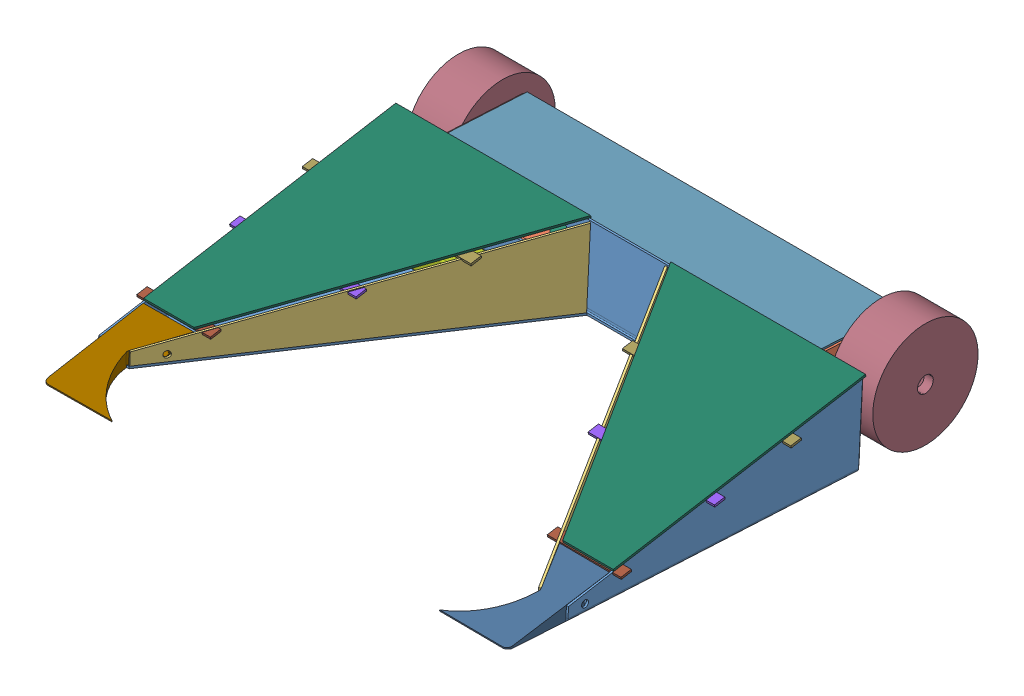
SolidWorks assembly Montagem, configuration Valor predeterminado. Lengths in mm.
Overall size (462 104.5 447.91).
26 component instances, 16 part files, 76 mates.
Components (placement in the parent):
- Base_triangulo-1: Base_triangulo [Valor predeterminado] at (18.3042 -43.9927 399.2511) size (446.01 74.77 283.15)
- Base_retangulo-1: Base_retangulo [Valor predeterminado] at (18.3042 -27.2137 284.6524) x (1 0 0) z (0 0.052336 0.99863) size (359.43 54.21 80.43)
- Parede_triangulo-1: Parede_triangulo [Valor predeterminado] at (-111.8741 2.0157 476.8292) x (0.866722 0.026105 0.498107) z (-0.498791 0.045361 0.865535) size (2 72 318)
- Parede_triangulo-2: Parede_triangulo [Valor predeterminado] at (146.7491 2.0679 477.8254) x (0.866722 -0.026105 -0.498107) z (0.498791 0.045361 0.865535) size (2 72 318)
- BaneBots_P60-4: BaneBots_P60 [Valor predeterminado] at (195.4588 13.3995 271.1437) x (1 0 0) z (0 0.99863 -0.052336) size (86.36 38.1 38.1)
- BaneBots_P60-5: BaneBots_P60 [Valor predeterminado] at (-158.3504 -24.6482 273.1377) x (-1 0 0) z (0 -0.99863 0.052336) size (86.36 38.1 38.1)
- D3548 - Moteur Brushless-1: D3548 - Moteur Brushless [Défaut] at (-62.2404 -6.6214 253.1168) x (0 0 -1) z (0 1 0) size (35.1 65.5 35.1)
- D3548 - Moteur Brushless-2: D3548 - Moteur Brushless [Défaut] at (101.8888 -6.6214 253.1168) x (0 -1 0) z (0 0 1) size (35.1 65.5 35.1)
- Bateria 5S Hockey-1: Bateria 5S Hockey [Valor predeterminado] at (27.8943 -9.4833 270.6699) x (1 0 0) z (0 0.052336 0.99863) size (155 47 40)
- ESC 100A Red BRick-3: ESC 100A Red BRick [Valor predeterminado] at (-127.7811 -20.8091 356.5766) x (1 0 0) z (0 -0.99863 0.052336) size (62 32 21)
- ESC 100A Red BRick-4: ESC 100A Red BRick [Valor predeterminado] at (152.2189 -20.8091 356.5766) x (1 0 0) z (0 -0.99863 0.052336) size (62 32 21)
- Estrutura2-1: Estrutura2 [Valor predeterminado] at (-152.6958 1.8403 455.8569) x (1 0 0) z (0 -0.985219 -0.1713) size (120 10 2)
- Estrutura2-2: Estrutura2 [Valor predeterminado] at (189.3042 2.4999 457.4545) x (1 0 0) z (0 -0.985862 -0.167558) size (120 10 2)
- garra_direita1-2: garra_direita1 [Valor predeterminado] at (-138.0433 -22.5414 552.8103) x (0.999967 -0.000423 -0.008066) z (0.008077 0.052334 0.998597) size (65 22 95)
- garra_esquerda1-2: garra_esquerda1 [Valor predeterminado] at (174.6649 -22.5414 552.8105) x (0.999967 0.000423 0.008066) z (-0.008077 0.052334 0.998597) size (65 22 95)
- Tampa Cubo Hockey-1: Tampa Cubo Hockey [Valor predeterminado] at (-206.4008 -8.1407 247.2055) x (0 0.000948 -1) z (-1 0 0) size (85 85 2) (hidden)
- Tampa Cubo Hockey-2: Tampa Cubo Hockey [Valor predeterminado] at (241.7009 -10.545 247.4023) x (0 0.058396 -0.998293) z (1 0 0) size (85 85 2) (hidden)
- Estrutura1-3: Estrutura1 [Valor predeterminado] at (214.3042 -12.59 546.239) x (1 0 0) z (0 -0.985862 -0.167558) size (70 10 2)
- Estrutura1-4: Estrutura1 [Valor predeterminado] at (-177.6958 -12.2175 544.0475) x (1 0 0) z (0 -0.985862 -0.167558) size (70 10 2)
- Estrutura3-3: Estrutura3 [Valor predeterminado] at (169.3042 14.8252 384.9361) x (1 0 0) z (0 -0.985862 -0.167558) size (160 10 2)
- Estrutura3-4: Estrutura3 [Valor predeterminado] at (-132.6958 14.5091 386.7961) x (1 0 0) z (0 -0.985862 -0.167558) size (160 10 2)
- Rodas-1: Rodas [Valor predeterminado] at (-161.4104 -6.6214 253.1168) x (0 0 1) z (-1 0 0) size (100 100 42)
- Rodas-2: Rodas [Valor predeterminado] at (198.0188 -6.6214 253.1168) x (0 0.046015 -0.998941) z (1 0 0) size (100 100 42)
- Tampa Traseira-1: Tampa Traseira [Valor predeterminado] at (16.7188 24.3293 270.4708) x (1 0 0) z (0 -0.99863 0.052336) size (355 80 2)
- Tampa Triangulos-1: Tampa Triangulos [Valor predeterminado] at (-204.6958 29.4357 310.9087) x (1 0 0) z (0 0.985862 0.167558) size (185 243 2)
- Tampa Triangulos-2: Tampa Triangulos [Valor predeterminado] at (241.3042 31.4074 311.2438) x (-1 0 0) z (0 -0.985862 -0.167558) size (185 243 2)
Mates (geometry in assembly coordinates):
- Coincidente8: coincident: line of Base_triangulo-1 through (-16.6958 -43.8894 317.7522) axis (-0.503936 0.045205 0.862557); line of ? through (-177.0242 -29.5074 592.1766) axis (0.503936 -0.045205 -0.862557)
- Coincidente9: coincident: point of Base_triangulo-1; unknown of ?
- Coincidente10: coincident: line of Base_triangulo-1 through (213.9686 -29.4773 592.7517) axis (-0.503936 -0.045205 -0.862557); line of ? through (213.6327 -29.5074 592.1766) axis (-0.503936 -0.045205 -0.862557)
- Coincidente11: coincident: unknown of Base_triangulo-1; unknown of ?
- Coincidente25: coincident: circle of assembly; circle of assembly; circle of BaneBots_P60-5; circle of D3548 - Moteur Brushless-1
- Coincidente26: coincident: circle of assembly; circle of assembly; circle of BaneBots_P60-4; circle of D3548 - Moteur Brushless-2
- Coincidente32: coincident: plane of assembly; plane of assembly; plane of Base_triangulo-1 through (18.3042 -39.5996 399.2875) normal (0 0.99863 -0.052336); plane of ESC 100A Red BRick-3 through (-127.7811 -41.7804 357.6757) normal (0 -0.99863 0.052336)
- Distância8: distance = 20 mm: plane of assembly; plane of assembly; plane of ESC 100A Red BRick-3 through (-152.6958 -42.8897 336.5084) normal (0 -0.052336 -0.99863); plane of Base_triangulo-1 through (18.3042 -127.729 320.9272) normal (0 0.052336 0.99863)
- Distância9: distance = 50 mm: plane of assembly; plane of assembly; plane of ESC 100A Red BRick-3 through (-152.6958 -41.2149 368.4646) normal (-1 0 0); plane of Base_triangulo-1 through (-202.6958 -261.4367 410.9135) normal (1 0 0)
- Coincidente35: coincident: plane of assembly; plane of assembly; plane of Base_triangulo-1 through (18.3042 -39.5996 399.2875) normal (0 0.99863 -0.052336); plane of ESC 100A Red BRick-4 through (152.2189 -41.7804 357.6757) normal (0 -0.99863 0.052336)
- Distância10: distance = 20 mm: plane of assembly; plane of assembly; plane of ESC 100A Red BRick-4 through (127.3042 -42.8897 336.5084) normal (0 -0.052336 -0.99863); plane of Base_triangulo-1 through (18.3042 -127.729 320.9272) normal (0 0.052336 0.99863)
- Distância14: distance = 50 mm: plane of assembly; plane of assembly; plane of ESC 100A Red BRick-4 through (189.3042 -41.2149 368.4646) normal (1 0 0); plane of Base_triangulo-1 through (239.3042 -261.4367 410.9135) normal (-1 0 0)
- Coincidente41: coincident: plane of Base_triangulo-1 through (-206.3396 27.6703 314.3825) normal (0 0.988467 0.151434); unknown of ?
- Coincidente42: coincident: plane of assembly; plane of assembly; plane of Base_triangulo-1 through (-202.6958 -261.4367 410.9135) normal (1 0 0); plane of Estrutura2-1 through (-202.6958 49.8327 464.2013) normal (-1 0 0)
- Coincidente49: coincident: plane of assembly; plane of assembly; plane of Base_triangulo-1 through (239.3042 -261.4367 410.9135) normal (-1 0 0); plane of Estrutura2-2 through (239.3042 50.5236 465.6167) normal (1 0 0)
- Coincidente50: coincident: plane of Base_triangulo-1 through (242.948 27.6703 314.3825) normal (0 0.988467 0.151434); unknown of ?
- Coincidente53: coincident: plane of Base_triangulo-1 through (18.3042 -39.5996 399.2875) normal (0 0.99863 -0.052336); plane of ? through (-161.8996 -28.6499 608.2191) normal (0 -0.99863 0.052336)
- Coincidente54: coincident: plane of Base_triangulo-1 through (-209.3396 -267.6428 411.2388) normal (1 0 0); plane of ? through (-209.3396 -7.7961 662.2016) normal (-1 0 0)
- Coincidente55: coincident: plane of Base_triangulo-1 through (-211.3396 -19.0455 607.215) normal (0 0.052336 0.99863); plane of ? through (-144.3396 -20.6871 607.301) normal (0 0.052336 0.99863)
- Coincidente58: coincident: plane of Base_triangulo-1 through (245.948 -267.6428 411.2388) normal (-1 0 0); plane of ? through (245.948 -7.7961 662.2016) normal (1 0 0)
- Coincidente59: coincident: plane of Base_triangulo-1 through (18.3042 -39.5996 399.2875) normal (0 0.99863 -0.052336); plane of ? through (198.508 -28.6499 608.2191) normal (0 -0.99863 0.052336)
- Coincidente60: coincident: plane of Base_triangulo-1 through (247.948 -494.3932 632.1269) normal (0 0.052336 0.99863); plane of ? through (180.948 -30.6734 607.8244) normal (0 0.052336 0.99863)
- Coincidente66: coincident: plane of assembly; plane of assembly; plane of Base_triangulo-1 through (-202.6958 -261.4367 410.9135) normal (1 0 0); plane of garra_direita1-2 through (-202.2738 -6.5573 647.6257) normal (-0.999967 0.000423 0.008066)
- Coincidente67: coincident: plane of Base_triangulo-1 through (-219.6958 -31.4746 592.8563) normal (0 0.052336 0.99863); unknown of ?
- Coincidente68: coincident: plane of assembly; plane of assembly; plane of Base_triangulo-1 through (239.3042 -261.4367 410.9135) normal (-1 0 0); plane of garra_esquerda1-2 through (238.8954 -6.5573 647.6258) normal (0.999967 0.000423 0.008066)
- Coincidente69: coincident: plane of Base_triangulo-1 through (-219.6958 -31.4746 592.8563) normal (0 0.052336 0.99863); unknown of ?
- Coincidente70: coincident: plane of assembly; plane of assembly; plane of Base_triangulo-1 through (18.3042 -39.5996 399.2875) normal (0 0.99863 -0.052336); plane of garra_esquerda1-2 through (191.5912 -29.4284 593.3645) normal (0 -0.99863 0.052336)
- Coincidente71: coincident: plane of assembly; plane of assembly; plane of Base_triangulo-1 through (18.3042 -39.5996 399.2875) normal (0 0.99863 -0.052336); plane of garra_direita1-2 through (-154.9696 -29.4284 593.3644) normal (0 -0.99863 0.052336)
- Coincidente72: coincident: plane of assembly; plane of assembly; plane of Base_triangulo-1 through (18.3042 -39.5996 399.2875) normal (0 0.99863 -0.052336); plane of Parede_triangulo-1 through (-175.4823 -29.4385 593.1731) normal (0 -0.99863 0.052336)
- Coincidente73: coincident: plane of assembly; plane of assembly; plane of Base_triangulo-1 through (-16.6958 -53.865 318.1596) normal (0.866722 0.026105 0.498107); plane of Parede_triangulo-1 through (-110.1407 2.0679 477.8254) normal (0.866722 0.026105 0.498107)
- Coincidente79: coincident: unknown of Base_triangulo-1; unknown of ?
- Coincidente80: coincident: plane of assembly; plane of assembly; plane of Base_triangulo-1 through (53.3042 -53.865 318.1596) normal (-0.866722 0.026105 0.498107); plane of Parede_triangulo-2 through (146.7491 2.0679 477.8254) normal (-0.866722 0.026105 0.498107)
- Coincidente81: coincident: plane of assembly; plane of assembly; plane of Base_triangulo-1 through (18.3042 -39.5996 399.2875) normal (0 0.99863 -0.052336); plane of Parede_triangulo-2 through (213.8242 -29.4907 592.1768) normal (0 -0.99863 0.052336)
- Coincidente82: coincident: unknown of Base_triangulo-1; unknown of ?
- Coincidente86: coincident: plane of assembly; plane of assembly; plane of Base_triangulo-1 through (-202.6958 -261.4367 410.9135) normal (1 0 0); plane of Estrutura2-1 through (-202.6958 49.8327 464.2013) normal (-1 0 0)
- Coincidente87: coincident: plane of Base_triangulo-1 through (-206.3396 28.147 323.3667) normal (0 0.985219 0.1713); plane of ? through (-154.3396 4.0474 461.9731) normal (0 0.985219 0.1713)
- Coincidente90: coincident: plane of assembly; plane of assembly; plane of Base_triangulo-1 through (241.3042 28.8941 314.0955) normal (0 0.985862 0.167558); plane of Estrutura2-2 through (189.3042 4.4717 457.7896) normal (0 0.985862 0.167558)
- Coincidente91: coincident: plane of assembly; plane of assembly; plane of Base_retangulo-1 through (-159.4104 -206.2534 294.0354) normal (1 0 0); plane of BaneBots_P60-5 through (-158.8504 -24.6482 273.1377) normal (-1 0 0)
- Coincidente96: coincident: plane of assembly; plane of assembly; plane of Base_retangulo-1 through (18.3042 -80.768 237.9265) normal (0 0.052336 0.99863); plane of BaneBots_P60-4 through (180.2188 -24.1057 234.957) normal (0 -0.052336 -0.99863)
- Coincidente101: coincident: plane of assembly; plane of assembly; plane of Base_retangulo-1 through (18.3042 -80.768 237.9265) normal (0 0.052336 0.99863); plane of BaneBots_P60-5 through (-143.1104 8.869 233.2288) normal (0 -0.052336 -0.99863)
- Coincidente105: coincident: plane of assembly; plane of assembly; plane of Base_triangulo-1 through (241.3042 28.8941 314.0955) normal (0 0.985862 0.167558); plane of Estrutura1-3 through (214.3042 -10.6182 546.5741) normal (0 0.985862 0.167558)
- Coincidente106: coincident: plane of assembly; plane of assembly; plane of Base_triangulo-1 through (239.3042 -261.4367 410.9135) normal (-1 0 0); plane of Estrutura1-3 through (239.3042 10.7872 550.2122) normal (1 0 0)
- Coincidente107: coincident: plane of Base_triangulo-1 through (-206.3396 28.147 323.3667) normal (0 0.985219 0.1713); unknown of ?
- Coincidente108: coincident: plane of assembly; plane of assembly; plane of Base_triangulo-1 through (-202.6958 -261.4367 410.9135) normal (1 0 0); plane of Estrutura1-4 through (-202.6958 11.1596 548.0207) normal (-1 0 0)
- Coincidente114: coincident: plane of assembly; plane of assembly; plane of Base_triangulo-1 through (241.3042 28.8941 314.0955) normal (0 0.985862 0.167558); plane of Estrutura3-3 through (169.3042 16.797 385.2713) normal (0 0.985862 0.167558)
- Coincidente115: coincident: plane of assembly; plane of assembly; plane of Base_triangulo-1 through (239.3042 -261.4367 410.9135) normal (-1 0 0); plane of Estrutura3-3 through (239.3042 82.5662 396.4495) normal (1 0 0)
- Coincidente118: coincident: plane of Base_triangulo-1 through (-206.3396 28.147 323.3667) normal (0 0.985219 0.1713); unknown of ?
- Coincidente119: coincident: plane of assembly; plane of assembly; plane of Base_triangulo-1 through (-202.6958 -261.4367 410.9135) normal (1 0 0); plane of Estrutura3-4 through (-202.6958 82.2501 398.3094) normal (-1 0 0)
- Coincidente123: coincident: plane of assembly; plane of assembly; plane of Base_retangulo-1 through (18.3042 -27.2137 284.6524) normal (0 0.99863 -0.052336); plane of Bateria 5S Hockey-1 through (-59.4104 -25.8025 311.58) normal (0 -0.99863 0.052336)
- Coincidente124: coincident: plane of assembly; plane of assembly; plane of Base_triangulo-1 through (18.3042 -127.8337 318.93) normal (0 -0.052336 -0.99863); plane of Base_retangulo-1 through (18.3042 -54.1941 315.0707) normal (0 0.052336 0.99863)
- Coincidente127: coincident: plane of assembly; plane of assembly; plane of Base_triangulo-1 through (-204.6958 28.8941 314.0955) normal (0 0.985862 0.167558); plane of Estrutura3-4 through (-132.6958 16.4809 387.1312) normal (0 0.985862 0.167558)
- Coincidente128: coincident: plane of assembly; plane of assembly; plane of Base_triangulo-1 through (241.3042 28.8941 314.0955) normal (0 0.985862 0.167558); plane of Estrutura3-3 through (169.3042 16.797 385.2713) normal (0 0.985862 0.167558)
- Coincidente129: coincident: plane of assembly; plane of assembly; plane of Base_triangulo-1 through (-204.6958 28.8941 314.0955) normal (0 0.985862 0.167558); plane of Estrutura1-4 through (-177.6958 -10.2458 544.3826) normal (0 0.985862 0.167558)
- Coincidente137: coincident: plane of assembly; plane of assembly; plane of Base_retangulo-1 through (18.3042 -54.2988 313.0734) normal (0 -0.052336 -0.99863); plane of Bateria 5S Hockey-1 through (27.8943 -7.3899 310.615) normal (0 0.052336 0.99863)
- Distância15: distance = 100 mm: plane of assembly; plane of assembly; plane of Base_retangulo-1 through (-159.4104 -206.2534 294.0354) normal (1 0 0); plane of Bateria 5S Hockey-1 through (-59.4104 21.1331 309.1202) normal (-1 0 0)
- Distância16: distance = 2 mm: plane of assembly; plane of assembly; plane of Base_retangulo-1 through (-158.1958 26.4452 310.8446) normal (0 0.99863 -0.052336); plane of Base_triangulo-1 through (-201.6958 28.4425 310.7399) normal (0 0.99863 -0.052336)
- Coincidente143: coincident: plane of assembly; plane of assembly; plane of Base_retangulo-1 through (18.3042 -80.768 237.9265) normal (0 0.052336 0.99863); plane of BaneBots_P60-4 through (180.2188 -24.1057 234.957) normal (0 -0.052336 -0.99863)
- Concêntrico17: concentric: cylinder of assembly; cylinder of assembly; cylinder of Base_retangulo-1 through (188.3388 1.764 231.5985) axis (0 -0.052336 -0.99863) radius 2.02; cylinder of BaneBots_P60-4 through (188.3388 1.8686 233.5957) axis (0 -0.052336 -0.99863) radius 2.0193
- Distância17: distance = 2 mm: plane of assembly; plane of assembly; plane of Base_retangulo-1 through (-138.1958 10.2523 231.1526) normal (1 0 0); plane of Base_triangulo-1 through (-138.1958 13.2594 307.6395) normal (1 0 0)
- Coincidente146: coincident: plane of assembly; plane of assembly; plane of Base_triangulo-1 through (-214.6958 -31.3996 593.967) normal (0.008147 0.052334 0.998596); plane of garra_direita1-2 through (-137.7202 -20.4481 592.7542) normal (-0.008077 -0.052334 -0.998597)
- Coincidente148: coincident: plane of assembly; plane of assembly; plane of Base_triangulo-1 through (251.3042 -31.3996 593.967) normal (-0.008147 0.052334 0.998596); plane of garra_esquerda1-2 through (174.3418 -20.4481 592.7543) normal (0.008077 -0.052334 -0.998597)
- Concêntrico20: concentric: cylinder of assembly; cylinder of assembly; cylinder of Base_retangulo-1 through (-151.7304 1.764 231.5985) axis (0 -0.052336 -0.99863) radius 2.02; cylinder of BaneBots_P60-5 through (-151.2304 1.8686 233.5957) axis (0 -0.052336 -0.99863) radius 2.0193
- Concêntrico21: concentric: cylinder of assembly; cone of assembly; cylinder of Base_retangulo-1 through (-114.9004 1.764 231.5985) axis (0 -0.052336 -0.99863) radius 2.02; cone of BaneBots_P60-5 through (-114.4004 2.4934 245.5174) axis (0 0.052336 0.99863)
- Coincidente149: coincident: plane of assembly; plane of assembly; plane of Base_triangulo-1 through (174.8042 13.2594 307.6395) normal (-1 0 0); plane of Base_retangulo-1 through (174.8042 10.2523 231.1526) normal (-1 0 0)
- Concêntrico22: concentric: cylinder of assembly; cylinder of assembly; cylinder of BaneBots_P60-5 through (-196.4504 -6.6214 253.1168) axis (1 0 0) radius 6.35; cylinder of Rodas-1 through (-161.4104 -6.6214 253.1168) axis (-1 0 0) radius 7.5
- Concêntrico23: concentric: cylinder of assembly; cylinder of assembly; cylinder of BaneBots_P60-4 through (233.5588 -6.6214 253.1168) axis (-1 0 0) radius 6.35; cylinder of Rodas-2 through (198.0188 -6.6214 253.1168) axis (1 0 0) radius 7.5
- Coincidente152: coincident: plane of assembly; plane of assembly; plane of Base_retangulo-1 through (198.0188 -206.2534 294.0354) normal (1 0 0); plane of Rodas-2 through (198.0188 -6.6214 253.1168) normal (-1 0 0)
- Coincidente153: coincident: plane of assembly; plane of assembly; plane of Base_retangulo-1 through (-161.4104 -206.2534 294.0354) normal (-1 0 0); plane of Rodas-1 through (-161.4104 -6.6214 253.1168) normal (1 0 0)
- Coincidente154: coincident: plane of assembly; plane of assembly; plane of Base_retangulo-1 through (-158.1958 22.2359 230.5256) normal (0 0.99863 -0.052336); plane of Tampa Traseira-1 through (16.7188 24.3293 270.4708) normal (0 0.99863 -0.052336)
- Coincidente155: coincident: plane of assembly; plane of assembly; plane of Base_retangulo-1 through (18.3042 -80.8726 235.9293) normal (0 -0.052336 -0.99863); plane of Tampa Traseira-1 through (-160.7812 20.2386 230.6303) normal (0 -0.052336 -0.99863)
- Coincidente156: coincident: plane of assembly; plane of assembly; plane of Base_triangulo-1 through (-204.6958 28.8941 314.0955) normal (0 0.985862 0.167558); plane of Tampa Triangulos-1 through (-204.6958 29.4357 310.9087) normal (0 -0.985862 -0.167558)
- Coincidente157: coincident: plane of assembly; plane of assembly; plane of Base_triangulo-1 through (-204.6958 -261.4367 410.9135) normal (-1 0 0); plane of Tampa Triangulos-1 through (-204.6958 31.4074 311.2438) normal (-1 0 0)
- Coincidente158: coincident: line of assembly; plane of assembly; line of Base_triangulo-1 through (238.3042 28.4425 310.7399) axis (-1 0 0); plane of Tampa Triangulos-1 through (-204.6958 31.4074 311.2438) normal (0 0.167558 -0.985862)
- Coincidente159: coincident: plane of assembly; plane of assembly; plane of Base_triangulo-1 through (241.3042 28.8941 314.0955) normal (0 0.985862 0.167558); plane of Tampa Triangulos-2 through (241.3042 29.4357 310.9087) normal (0 -0.985862 -0.167558)
- Coincidente160: coincident: plane of assembly; plane of assembly; plane of Base_triangulo-1 through (241.3042 -261.4367 410.9135) normal (1 0 0); plane of Tampa Triangulos-2 through (241.3042 29.4357 310.9087) normal (1 0 0)
- Coincidente161: coincident: line of assembly; plane of assembly; line of Base_triangulo-1 through (238.3042 28.4425 310.7399) axis (-1 0 0); plane of Tampa Triangulos-2 through (241.3042 29.4357 310.9087) normal (0 0.167558 -0.985862)
